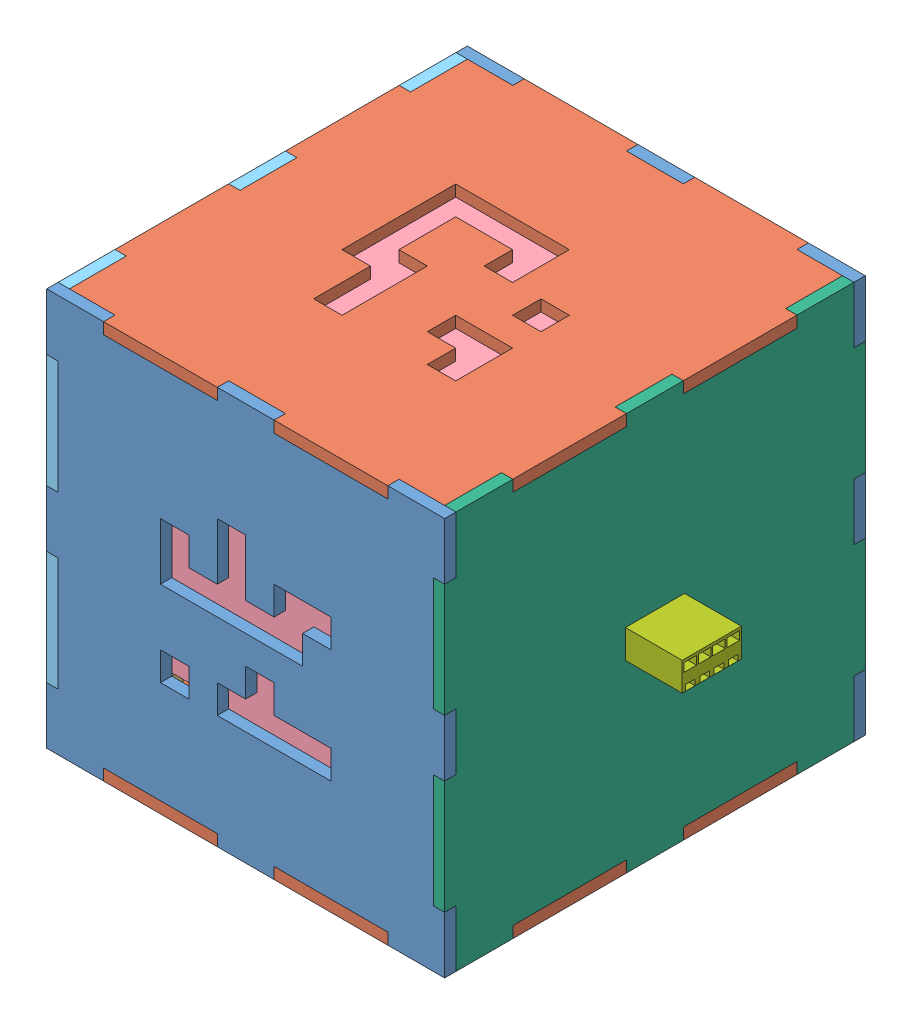
SolidWorks assembly Module_Assem, configuration Default. Lengths in mm.
Overall size (80 70 74).
16 component instances, 8 part files, 23 mates.
Components (placement in the parent):
- Module_Front-1: Module_Front [Default] at (-38.8904 -9.0649 78.7698) size (70 70 2)
- Module_TB-1: Module_TB [Default] at (-38.8904 23.9351 41.7698) x (1 0 0) z (0 1 0) size (70 74 2)
- fixer-1: fixer [Default] at (-10.8904 -42.0649 11.7698) size (10 10 10)
- fixer-2: fixer [Default] at (-66.8904 -42.0649 11.7698) size (10 10 10)
- fixer-3: fixer [Default] at (-66.8904 -42.0649 71.7698) size (10 10 10)
- fixer-4: fixer [Default] at (-10.8904 -42.0649 71.7698) size (10 10 10)
- Black_Cover-1: Black_Cover [Default] at (-39.9297 -11.313 6.7698) size (45 45 2)
- Module_LR_Female-1: Module_LR_Female [Default] at (-73.8904 -9.0649 41.7698) x (0 0 1) z (-1 0 0) size (74 70 2)
- Module_LR_Male-1: Module_LR_Male [Default] at (-3.8904 -9.0649 41.7698) x (0 0 -1) z (1 0 0) size (74 70 2)
- Black_Cover-2: Black_Cover [Default] at (-38.5298 -42.0649 41.0428) x (1 0 0) z (0 1 0) size (45 45 2)
- Module_Front-3: Module_Front [Default] at (-38.8904 -9.0649 6.7698) size (70 70 2)
- Module_TB-3: Module_TB [Default] at (-38.8904 -44.0649 41.7698) x (1 0 0) z (0 1 0) size (70 74 2)
- Black_Cover-3: Black_Cover [Default] at (-38.4275 -4.4967 74.0738) size (45 45 2)
- Black_Cover-4: Black_Cover [Default] at (-38.697 23.9351 42.304) x (1 0 0) z (0 -1 0) size (45 45 2)
- port_1-1: port_1 [Default] at (-5.8904 -6.7008 48.1688) x (0 0 -1) z (1 0 0) size (10.41 5 12)
- port_2-1: port_2 [Default] at (-73.8904 -5.5149 35.5048) x (0 0 1) z (-1 0 0) size (12.53 7.1 20.5)
Mates (geometry in assembly coordinates):
- Coincident10: coincident aligned: plane of Module_Front-1 through (-73.8904 25.9351 76.7698) normal (0 1 0); plane of Module_TB-1 through (-38.8904 25.9351 41.7698) normal (0 1 0)
- Coincident11: coincident aligned: plane of Module_Front-1 through (-38.8904 -9.0649 78.7698) normal (0 0 1); plane of Module_TB-1 through (-38.8904 25.9351 78.7698) normal (0 0 1)
- Coincident21: coincident anti-aligned: plane of Module_Front-1 through (-38.8904 -9.0649 76.7698) normal (0 0 -1); plane of fixer-3 through (-71.8904 -32.0649 76.7698) normal (0 0 1)
- Coincident26: coincident anti-aligned: plane of Module_Front-1 through (-38.8904 -9.0649 76.7698) normal (0 0 -1); plane of fixer-4 through (-15.8904 -32.0649 76.7698) normal (0 0 1)
- Coincident30: coincident aligned: plane of Module_Front-1 through (-38.8904 -9.0649 78.7698) normal (0 0 1); plane of Module_LR_Female-1 through (-71.8904 -9.0649 78.7698) normal (0 0 1)
- Coincident34: coincident aligned: plane of Module_TB-1 through (-38.8904 25.9351 41.7698) normal (0 1 0); plane of Module_LR_Female-1 through (-71.8904 25.9351 6.7698) normal (0 1 0)
- Coincident35: coincident anti-aligned: plane of Module_Front-1 through (-71.8904 -9.0649 76.7698) normal (-1 0 0); plane of Module_LR_Female-1 through (-71.8904 -9.0649 41.7698) normal (1 0 0)
- Coincident37: coincident anti-aligned: plane of Module_Front-1 through (-5.8904 -9.0649 76.7698) normal (1 0 0); plane of Module_LR_Male-1 through (-5.8904 -9.0649 41.7698) normal (-1 0 0)
- Coincident39: coincident aligned: plane of Module_TB-1 through (-38.8904 25.9351 41.7698) normal (0 1 0); plane of Module_LR_Male-1 through (-5.8904 25.9351 76.7698) normal (0 1 0)
- Coincident41: coincident anti-aligned: plane of Module_TB-1 through (-71.8904 25.9351 6.7698) normal (0 0 -1); plane of Module_Front-3 through (-38.8904 -9.0649 6.7698) normal (0 0 1)
- Coincident42: coincident aligned: plane of Module_LR_Female-1 through (-73.8904 -9.0649 41.7698) normal (-1 0 0); plane of Module_Front-3 through (-73.8904 -44.0649 4.7698) normal (-1 0 0)
- Coincident43: coincident aligned: plane of Module_TB-1 through (-38.8904 25.9351 41.7698) normal (0 1 0); plane of Module_Front-3 through (-73.8904 25.9351 4.7698) normal (0 1 0)
- Coincident44: coincident aligned: plane of Module_LR_Male-1 through (-3.8904 -9.0649 41.7698) normal (1 0 0); plane of Module_TB-3 through (-3.8904 -42.0649 41.7698) normal (1 0 0)
- Coincident45: coincident aligned: plane of Module_Front-3 through (-38.8904 -9.0649 4.7698) normal (0 0 -1); plane of Module_TB-3 through (-38.8904 -42.0649 4.7698) normal (0 0 -1)
- Coincident46: coincident aligned: plane of Module_Front-3 through (-73.8904 -44.0649 4.7698) normal (0 -1 0); plane of Module_TB-3 through (-38.8904 -44.0649 41.7698) normal (0 -1 0)
- Coincident47: coincident anti-aligned: plane of Module_TB-1 through (-38.8904 23.9351 41.7698) normal (0 -1 0); plane of Black_Cover-4 through (-38.697 23.9351 42.304) normal (0 1 0)
- Coincident50: coincident anti-aligned: plane of Black_Cover-1 through (-39.9297 -11.313 6.7698) normal (0 0 -1); plane of Module_Front-3 through (-38.8904 -9.0649 6.7698) normal (0 0 1)
- Coincident51: coincident: plane of Module_LR_Female-1 through (-63.8904 -5.5149 35.5048) normal (0 -1 0); plane of port_2-1 through (-64.8904 -5.5149 35.5048) normal (0 1 0)
- Coincident52: coincident: plane of Module_LR_Female-1 through (-63.8904 -12.6149 35.5048) normal (0 0 1); plane of port_2-1 through (-64.8904 -5.5149 35.5048) normal (0 0 -1)
- Coincident53: coincident aligned: plane of Module_LR_Female-1 through (-73.8904 -9.0649 41.7698) normal (-1 0 0); plane of port_2-1 through (-73.8904 -5.5149 35.5048) normal (-1 0 0)
- Coincident54: coincident anti-aligned: plane of Module_LR_Male-1 through (-13.8904 -6.5649 46.9748) normal (0 -1 0); plane of port_1-1 through (25.0806 -6.5649 46.9748) normal (0 1 0)
- Coincident55: coincident anti-aligned: plane of Module_LR_Male-1 through (-13.8904 -11.5649 36.5648) normal (0 0 1); plane of port_1-1 through (25.0806 -6.5649 36.5648) normal (0 0 -1)
- Coincident56: coincident aligned: plane of Module_LR_Male-1 through (-5.8904 -9.0649 41.7698) normal (-1 0 0); plane of port_1-1 through (-5.8904 -6.7008 48.1688) normal (-1 0 0)
